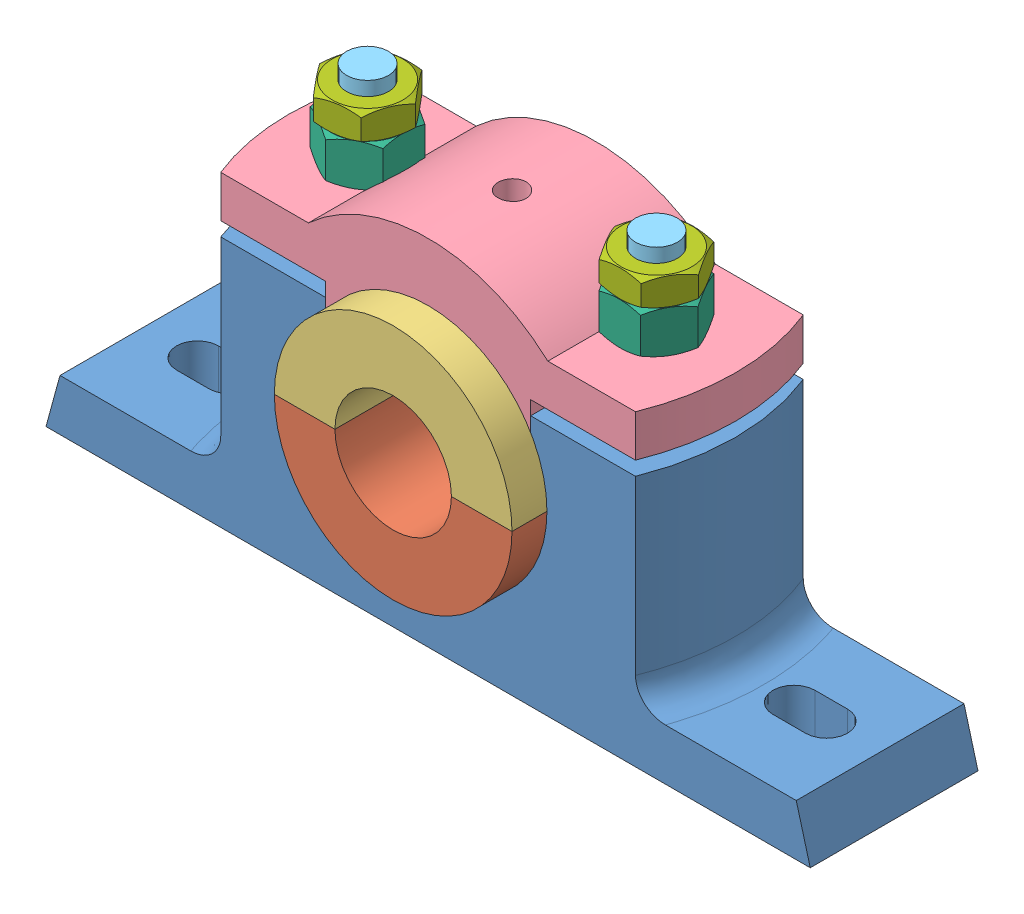
SolidWorks assembly Assem2, configuration Default. Lengths in mm.
Overall size (164 84 51).
10 component instances, 7 part files, 22 mates.
Components (placement in the parent):
- CASTING-1: CASTING [Default] at (84.4542 62.173 129.5272) size (164 54 36)
- BUSH2-1: BUSH2 [Default] at (84.4542 100.173 129.5272) x (0 0 1) z (-1 0 0) size (51 25.5 51)
- BUSH-1: BUSH [Default] at (84.4542 100.173 129.5272) x (0 0 1) z (1 0 0) size (51 25.5 51)
- cap-1: cap [Default] at (84.4542 100.173 129.5272) x (1 0 0) z (0 -1 0) size (96 36 32)
- bolt-1: bolt [Default] at (115.4542 64.173 129.5272) x (0 0 -1) z (1 0 0) size (19 82 19)
- nut-1: nut [Default] at (115.4542 132.673 129.5272) x (0.871051 0 -0.491193) z (0.491193 0 0.871051) size (15.59 9 18)
- bolt-2: bolt [Default] at (53.4542 64.173 129.5272) size (19 82 19)
- nut-2: nut [Default] at (53.4542 132.673 129.5272) size (15.59 9 18)
- locknut-1: locknut [Default] at (53.4542 140.173 129.5272) x (0.988363 0 -0.152112) z (0.152112 0 0.988363) size (18 6 15.59)
- locknut-2: locknut [Default] at (115.4542 140.173 129.5272) size (18 6 15.59)
Mates (geometry in assembly coordinates):
- Concentric5: concentric aligned: cylinder of CASTING-1 through (84.4542 81.173 129.5272) axis (0 1 0) radius 3; cylinder of BUSH2-1 through (84.4542 76.673 129.5272) axis (0 1 0) radius 3
- Concentric6: concentric anti-aligned: cylinder of CASTING-1 through (84.4542 100.173 147.5272) axis (0 0 -1) radius 19; cylinder of BUSH2-1 through (84.4542 100.173 155.0272) axis (0 0 1) radius 17.5
- Concentric7: concentric aligned: cylinder of BUSH2-1 through (84.4542 100.173 155.0272) axis (0 0 -1) radius 12.5; cylinder of BUSH-1 through (84.4542 100.173 155.0272) axis (0 0 -1) radius 12.5
- Coincident9: coincident aligned: plane of BUSH2-1 through (84.4542 100.173 155.0272) normal (0 0 1); plane of BUSH-1 through (84.4542 100.173 155.0272) normal (0 0 1)
- Coincident13: coincident anti-aligned: plane of BUSH2-1 through (84.4542 100.173 129.5272) normal (0 1 0); plane of BUSH-1 through (84.4542 100.173 129.5272) normal (0 -1 0)
- Concentric9: concentric anti-aligned: cylinder of BUSH-1 through (84.4542 100.173 155.0272) axis (0 0 1) radius 17.5; cylinder of cap-1 through (84.4542 100.173 147.5272) axis (0 0 -1) radius 19
- Concentric10: concentric aligned: cylinder of CASTING-1 through (53.4542 116.173 129.5272) axis (0 1 0) radius 4.5; cylinder of cap-1 through (53.4542 92.173 129.5272) axis (0 1 0) radius 4.5
- Concentric25: concentric anti-aligned: cylinder of CASTING-1 through (115.4542 116.173 129.5272) axis (0 1 0) radius 4.5; cylinder of bolt-1 through (115.4542 146.173 129.5272) axis (0 -1 0) radius 4.5
- Coincident33: coincident anti-aligned: plane of CASTING-1 through (84.4542 70.173 129.5272) normal (0 -1 0); plane of bolt-1 through (115.4542 70.173 129.5272) normal (0 1 0)
- Parallel8: parallel anti-aligned: plane of CASTING-1 through (125.4542 70.173 139.5272) normal (-1 0 0); plane of bolt-1 through (124.9542 70.173 139.0272) normal (1 0 0)
- Coincident34: coincident anti-aligned: plane of cap-1 through (134.4542 128.173 147.5272) normal (0 1 0); plane of nut-1 through (115.4542 128.173 129.5272) normal (0 -1 0)
- Concentric27: concentric aligned: cylinder of bolt-1 through (115.4542 146.173 129.5272) axis (0 -1 0) radius 4.5; cylinder of nut-1 through (115.4542 137.173 129.5272) axis (0 -1 0) radius 4.5
- Concentric28: concentric anti-aligned: cylinder of CASTING-1 through (53.4542 116.173 129.5272) axis (0 1 0) radius 4.5; cylinder of bolt-2 through (53.4542 146.173 129.5272) axis (0 -1 0) radius 4.5
- Coincident35: coincident anti-aligned: plane of CASTING-1 through (84.4542 70.173 129.5272) normal (0 -1 0); plane of bolt-2 through (53.4542 70.173 129.5272) normal (0 1 0)
- Parallel9: parallel anti-aligned: plane of CASTING-1 through (43.4542 70.173 119.5272) normal (0 0 1); plane of bolt-2 through (43.9542 70.173 120.0272) normal (0 0 -1)
- Concentric29: concentric aligned: cylinder of bolt-2 through (53.4542 146.173 129.5272) axis (0 -1 0) radius 4.5; cylinder of nut-2 through (53.4542 137.173 129.5272) axis (0 -1 0) radius 4.5
- Coincident37: coincident anti-aligned: plane of cap-1 through (34.4542 128.173 147.5272) normal (0 1 0); plane of nut-2 through (53.4542 128.173 129.5272) normal (0 -1 0)
- Concentric30: concentric anti-aligned: cylinder of bolt-2 through (53.4542 146.173 129.5272) axis (0 -1 0) radius 4.5; cylinder of locknut-1 through (53.4542 137.173 129.5272) axis (0 1 0) radius 4.5
- Concentric31: concentric anti-aligned: cylinder of bolt-2 through (53.4542 146.173 129.5272) axis (0 -1 0) radius 4.5; cylinder of locknut-1 through (53.4542 137.173 129.5272) axis (0 1 0) radius 4.5
- Coincident39: coincident anti-aligned: plane of nut-2 through (53.4542 137.173 129.5272) normal (0 1 0); plane of locknut-1 through (53.4542 137.173 129.5272) normal (0 -1 0)
- Concentric33: concentric anti-aligned: cylinder of bolt-1 through (115.4542 146.173 129.5272) axis (0 -1 0) radius 4.5; cylinder of locknut-2 through (115.4542 137.173 129.5272) axis (0 1 0) radius 4.5
- Coincident41: coincident anti-aligned: plane of nut-1 through (115.4542 137.173 129.5272) normal (0 1 0); plane of locknut-2 through (115.4542 137.173 129.5272) normal (0 -1 0)
